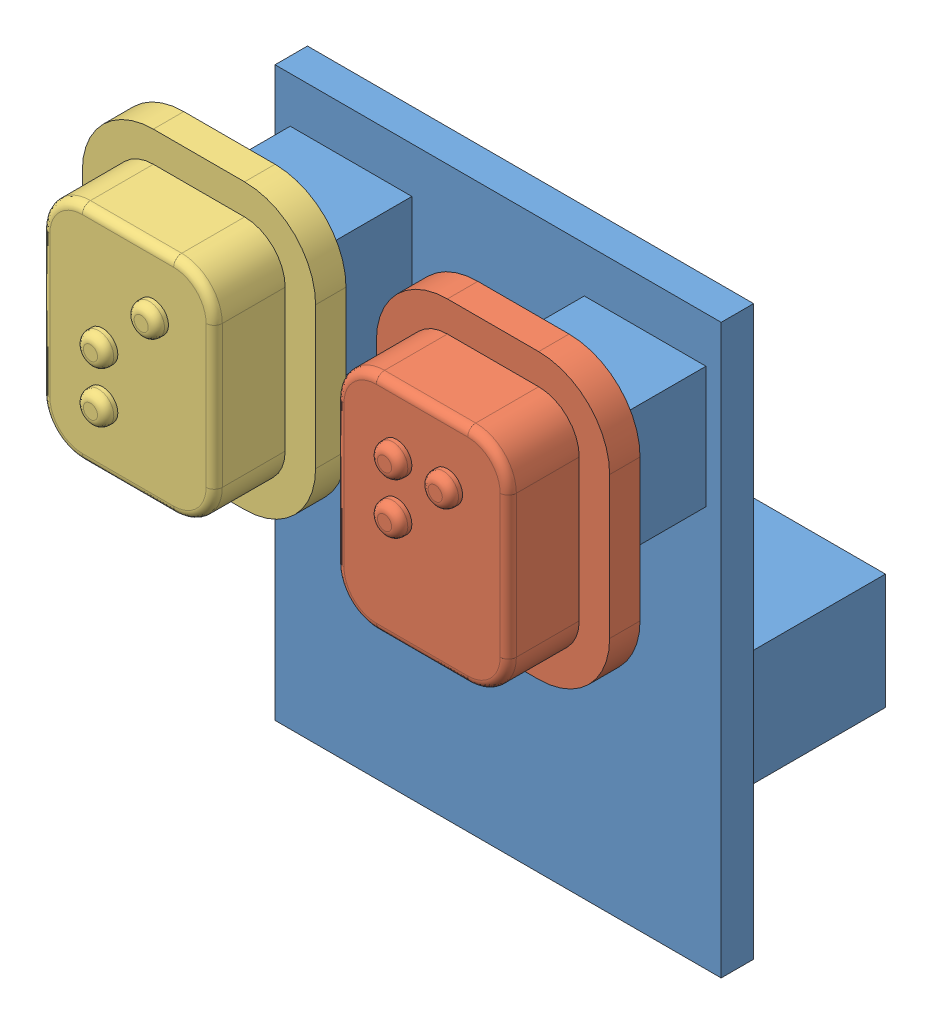
SolidWorks assembly Button PCB, configuration Default. Lengths in mm.
Overall size (23 28.25 20.2).
3 component instances, 3 part files, 7 mates.
Components (placement in the parent):
- Button PCB-1: Button PCB [Default] at (17.5795 4.2128 10.4054) size (22 28 18.6)
- ButtonF-1: ButtonF [Default] at (24.8295 26.9628 23.0054) x (1 0 0) z (0 -1 0) size (8.5 5.6 11)
- ButtonS-1: ButtonS [Default] at (10.3295 26.9628 23.0054) x (1 0 0) z (0 -1 0) size (8.5 5.6 11)
Mates (geometry in assembly coordinates):
- Coincident1: coincident anti-aligned: plane of Button PCB-1 through (10.3295 26.9628 22.0054) normal (0 0 1); plane of ButtonS-1 through (12.5795 23.4628 22.0054) normal (0 0 -1)
- Width1: width: plane of ButtonS-1 through (11.8795 28.5128 22.0054) normal (-0.99863 0 -0.052336); plane of ButtonS-1 through (8.7795 28.5128 22.0054) normal (0.99863 0 -0.052336); cone of Button PCB-1 through (10.3295 26.9628 22.0054) axis (0 0 1)
- Width2: width: plane of ButtonS-1 through (8.7795 28.5128 22.0054) normal (0 -0.99863 -0.052336); plane of ButtonS-1 through (8.7795 25.4128 22.0054) normal (0 0.99863 -0.052336); cone of Button PCB-1 through (10.3295 26.9628 22.0054) axis (0 0 1)
- Coincident3: coincident aligned: plane of ButtonF-1 through (27.0795 23.4628 23.0054) normal (0 0 1); plane of ButtonS-1 through (12.5795 23.4628 23.0054) normal (0 0 1)
- Coincident4: coincident aligned: plane of ButtonF-1 through (22.5795 32.4628 18.0054) normal (0 1 0); plane of ButtonS-1 through (8.0795 32.4628 18.0054) normal (0 1 0)
- Width3: width: plane of ButtonF-1 through (23.2795 28.5128 22.0054) normal (0 -0.99863 -0.052336); plane of ButtonF-1 through (23.2795 25.4128 22.0054) normal (0 0.99863 -0.052336); cone of Button PCB-1 through (24.8295 26.9628 22.0054) axis (0 0 1)
- Width4: width: plane of ButtonF-1 through (23.2795 28.5128 22.0054) normal (0.99863 0 -0.052336); plane of ButtonF-1 through (26.3795 28.5128 22.0054) normal (-0.99863 0 -0.052336); cone of Button PCB-1 through (24.8295 26.9628 22.0054) axis (0 0 1)
